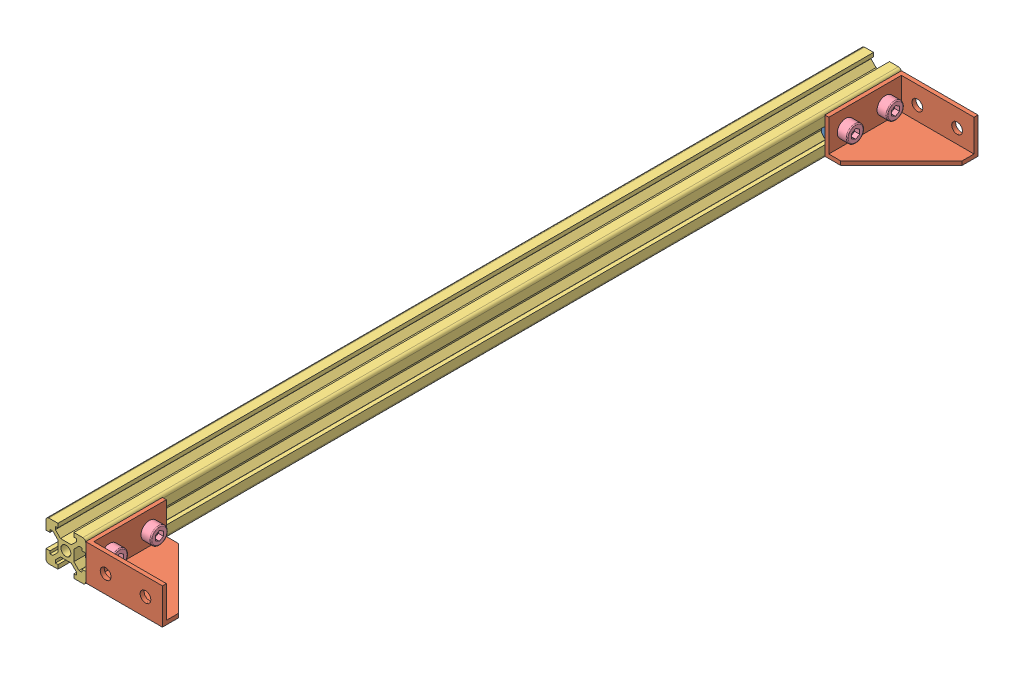
SolidWorks assembly framepart_410_1, configuration По умолчанию. Lengths in mm.
Overall size (58.5 20 410).
11 component instances, 4 part files, 24 mates.
Components (placement in the parent):
- Пазовый сухарь М5-1: Пазовый сухарь М5 [По умолчанию] at (232.8619 -146.0403 344.8162) x (0 -1 0) z (0 0 1) size (9.4 4.5 10.2)
- Уголок_40х40-1: Уголок_40х40 [По умолчанию] at (276.3619 -159.7403 319.9162) x (-1 0 0) z (0 1 0) size (38.5 38.5 18)
- Пазовый сухарь М5-2: Пазовый сухарь М5 [По умолчанию] at (232.8619 -146.0403 324.8162) x (0 -1 0) z (0 0 1) size (9.4 4.5 10.2)
- Пазовый сухарь М5-3: Пазовый сухарь М5 [По умолчанию] at (232.8619 -146.0403 694.8162) x (0 -1 0) z (0 0 1) size (9.4 4.5 10.2)
- Пазовый сухарь М5-4: Пазовый сухарь М5 [По умолчанию] at (232.8619 -146.0403 714.8162) x (0 -1 0) z (0 0 1) size (9.4 4.5 10.2)
- Extrude_20x20x410-2: Extrude_20x20x410 [По умолчанию] at (217.8619 -160.7403 319.9162) size (20 20 410)
- Уголок_40х40-2: Уголок_40х40 [По умолчанию] at (237.8619 -159.7403 691.4162) x (0 0 1) z (0 1 0) size (38.5 38.5 18)
- socket head cap screw_din-1: socket head cap screw_din [DIN 912 M5 x 8 --- 8N] at (244.8619 -150.7403 699.9162) x (-1 0 0) z (0 0 -1) size (13 8.5 8.5)
- socket head cap screw_din-2: socket head cap screw_din [DIN 912 M5 x 8 --- 8N] at (244.8619 -150.7403 719.9162) x (-1 0 0) z (0 0 -1) size (13 8.5 8.5)
- socket head cap screw_din-3: socket head cap screw_din [DIN 912 M5 x 8 --- 8N] at (244.8619 -150.7403 329.9162) x (-1 0 0) z (0 0 -1) size (13 8.5 8.5)
- socket head cap screw_din-4: socket head cap screw_din [DIN 912 M5 x 8 --- 8N] at (244.8619 -150.7403 349.9162) x (-1 0 0) z (0 0 -1) size (13 8.5 8.5)
Mates (geometry in assembly coordinates):
- Совпадение15: coincident: plane of Уголок_40х40-1 through (237.8619 -141.7403 319.9162) normal (-1 0 0); plane of Extrude_20x20x410-2 through (237.8619 -146.7403 729.9162) normal (1 0 0)
- Ширина5: width: plane of Extrude_20x20x410-2 through (237.8619 -154.7403 729.9162) normal (0 1 0); plane of Extrude_20x20x410-2 through (235.8619 -146.7403 729.9162) normal (0 -1 0); plane of Пазовый сухарь М5-1 through (235.8619 -153.6403 355.0162) normal (0 -1 0); plane of Пазовый сухарь М5-1 through (237.3619 -147.8403 355.0162) normal (0 1 0)
- Совпадение17: coincident: plane of Пазовый сухарь М5-1 through (235.8619 -155.4403 355.0162) normal (1 0 0); plane of Extrude_20x20x410-2 through (235.8619 -145.4403 729.9162) normal (-1 0 0)
- Ширина6: width: plane of Extrude_20x20x410-2 through (237.8619 -154.7403 729.9162) normal (0 1 0); plane of Extrude_20x20x410-2 through (235.8619 -146.7403 729.9162) normal (0 -1 0); plane of Пазовый сухарь М5-2 through (235.8619 -153.6403 335.0162) normal (0 -1 0); plane of Пазовый сухарь М5-2 through (237.3619 -147.8403 335.0162) normal (0 1 0)
- Совпадение18: coincident: plane of Пазовый сухарь М5-2 through (235.8619 -155.4403 335.0162) normal (1 0 0); plane of Extrude_20x20x410-2 through (235.8619 -145.4403 729.9162) normal (-1 0 0)
- Концентричный11: concentric: cylinder of Уголок_40х40-1 through (239.8619 -150.7403 329.9162) axis (1 0 0) radius 2.75; cylinder of Пазовый сухарь М5-2 through (237.3619 -150.7403 329.9162) axis (1 0 0) radius 2.6
- Концентричный12: concentric: cylinder of Пазовый сухарь М5-1 through (237.3619 -150.7403 349.9162) axis (1 0 0) radius 2.6; cylinder of Уголок_40х40-1 through (239.8619 -150.7403 349.9162) axis (1 0 0) radius 2.75
- Ширина7: width: plane of Extrude_20x20x410-2 through (237.8619 -154.7403 729.9162) normal (0 1 0); plane of Extrude_20x20x410-2 through (235.8619 -146.7403 729.9162) normal (0 -1 0); plane of Пазовый сухарь М5-3 through (235.8619 -153.6403 705.0162) normal (0 -1 0); plane of Пазовый сухарь М5-3 through (237.3619 -147.8403 705.0162) normal (0 1 0)
- Совпадение19: coincident: plane of Пазовый сухарь М5-3 through (235.8619 -155.4403 705.0162) normal (1 0 0); plane of Extrude_20x20x410-2 through (235.8619 -145.4403 729.9162) normal (-1 0 0)
- Ширина8: width: plane of Extrude_20x20x410-2 through (237.8619 -154.7403 729.9162) normal (0 1 0); plane of Extrude_20x20x410-2 through (235.8619 -146.7403 729.9162) normal (0 -1 0); plane of Пазовый сухарь М5-4 through (235.8619 -153.6403 725.0162) normal (0 -1 0); plane of Пазовый сухарь М5-4 through (237.3619 -147.8403 725.0162) normal (0 1 0)
- Совпадение20: coincident: plane of Пазовый сухарь М5-4 through (235.8619 -155.4403 725.0162) normal (1 0 0); plane of Extrude_20x20x410-2 through (235.8619 -145.4403 729.9162) normal (-1 0 0)
- Совпадение21: coincident: plane of Уголок_40х40-1 through (276.3619 -141.7403 319.9162) normal (0 0 -1); plane of Extrude_20x20x410-2 through (217.8619 -160.7403 319.9162) normal (0 0 -1)
- Концентричный162: concentric: cylinder of Пазовый сухарь М5-4 through (237.3619 -150.7403 719.9162) axis (1 0 0) radius 2.6; cylinder of Уголок_40х40-2 through (239.8619 -150.7403 719.9162) axis (1 0 0) radius 2.75
- Концентричный163: concentric: cylinder of Пазовый сухарь М5-3 through (237.3619 -150.7403 699.9162) axis (1 0 0) radius 2.6; cylinder of Уголок_40х40-2 through (239.8619 -150.7403 699.9162) axis (1 0 0) radius 2.75
- Совпадение252: coincident: plane of Extrude_20x20x410-2 through (237.8619 -160.7403 729.9162) normal (1 0 0); plane of Уголок_40х40-2 through (237.8619 -141.7403 691.4162) normal (-1 0 0)
- Совпадение253: coincident: plane of Extrude_20x20x410-2 through (217.8619 -160.7403 729.9162) normal (0 0 1); plane of Уголок_40х40-2 through (237.8619 -141.7403 729.9162) normal (0 0 1)
- Концентричный1641: concentric: cylinder of Уголок_40х40-2 through (239.8619 -150.7403 699.9162) axis (1 0 0) radius 2.75; cylinder of socket head cap screw_din-1 through (276.6119 -150.7403 699.9162) axis (1 0 0) radius 2.5
- Совпадение2541: coincident: plane of Уголок_40х40-2 through (239.8619 -157.7403 691.4162) normal (1 0 0); plane of socket head cap screw_din-1 through (239.8619 -146.4903 699.9162) normal (-1 0 0)
- Концентричный1651: concentric: cylinder of Уголок_40х40-2 through (239.8619 -150.7403 719.9162) axis (1 0 0) radius 2.75; cylinder of socket head cap screw_din-2 through (276.6119 -150.7403 719.9162) axis (1 0 0) radius 2.5
- Совпадение2551: coincident: plane of Уголок_40х40-2 through (239.8619 -157.7403 691.4162) normal (1 0 0); plane of socket head cap screw_din-2 through (239.8619 -146.4903 719.9162) normal (-1 0 0)
- Концентричный1661: concentric: cylinder of Уголок_40х40-1 through (239.8619 -150.7403 329.9162) axis (1 0 0) radius 2.75; cylinder of socket head cap screw_din-3 through (276.6119 -150.7403 329.9162) axis (1 0 0) radius 2.5
- Совпадение2561: coincident: plane of Уголок_40х40-1 through (239.8619 -157.7403 321.9162) normal (1 0 0); plane of socket head cap screw_din-3 through (239.8619 -146.4903 329.9162) normal (-1 0 0)
- Концентричный1671: concentric: cylinder of Уголок_40х40-1 through (239.8619 -150.7403 349.9162) axis (1 0 0) radius 2.75; cylinder of socket head cap screw_din-4 through (276.6119 -150.7403 349.9162) axis (1 0 0) radius 2.5
- Совпадение2571: coincident: plane of Уголок_40х40-1 through (239.8619 -157.7403 321.9162) normal (1 0 0); plane of socket head cap screw_din-4 through (239.8619 -146.4903 349.9162) normal (-1 0 0)
